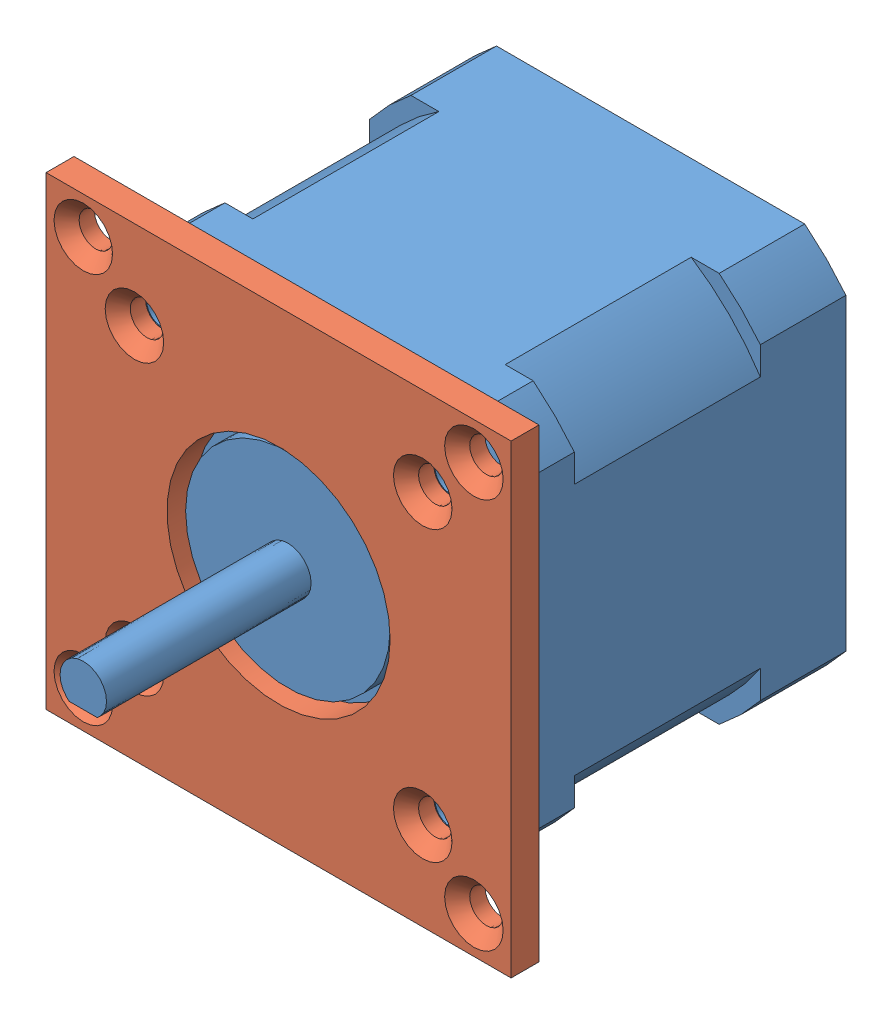
SolidWorks assembly Assem2, configuration Default. Lengths in mm.
Overall size (50 51.4 61).
4 component instances, 2 part files, 3 mates.
Components (placement in the parent):
- NEMA17-42A0C-1: NEMA17-42A0C [Default] at (-55.4166 7.897 -19.7183) size (42 47.4 61)
  - NEMA17-42A0C.step-1: NEMA17-42A0C.step [Default] at origin size (42 47.4 61)
    - NEMA17-42A02C-Body.step-1: NEMA17-42A02C-Body.step [Default] at origin size (42 47.4 61)
- Plate-2: Plate [Default] at (-55.4166 7.897 -19.7183) x (0 1 0) z (1 0 0) size (50 3 50)
Mates (geometry in assembly coordinates):
- Concentric2: concentric: cylinder of NEMA17-42A0C-1/NEMA17-42A0C.step-1/NEMA17-42A02C-Body.step-1 through (-55.4166 7.897 -19.7183) axis (0 0 -1) radius 11; cylinder of Plate-2 through (-55.4166 7.897 -16.7183) axis (0 0 1) radius 12
- Perpendicular2: perpendicular: plane of NEMA17-42A0C-1/NEMA17-42A0C.step-1/NEMA17-42A02C-Body.step-1 through (-38.8466 -13.103 -19.7183) normal (0 -1 0); plane of Plate-2 through (-30.4166 32.897 -16.7183) normal (1 0 0)
- Coincident4: coincident anti-aligned: plane of NEMA17-42A0C-1/NEMA17-42A0C.step-1/NEMA17-42A02C-Body.step-1 through (-55.4166 7.897 -19.7183) normal (0 0 1); plane of Plate-2 through (-55.4166 7.897 -19.7183) normal (0 0 -1)
